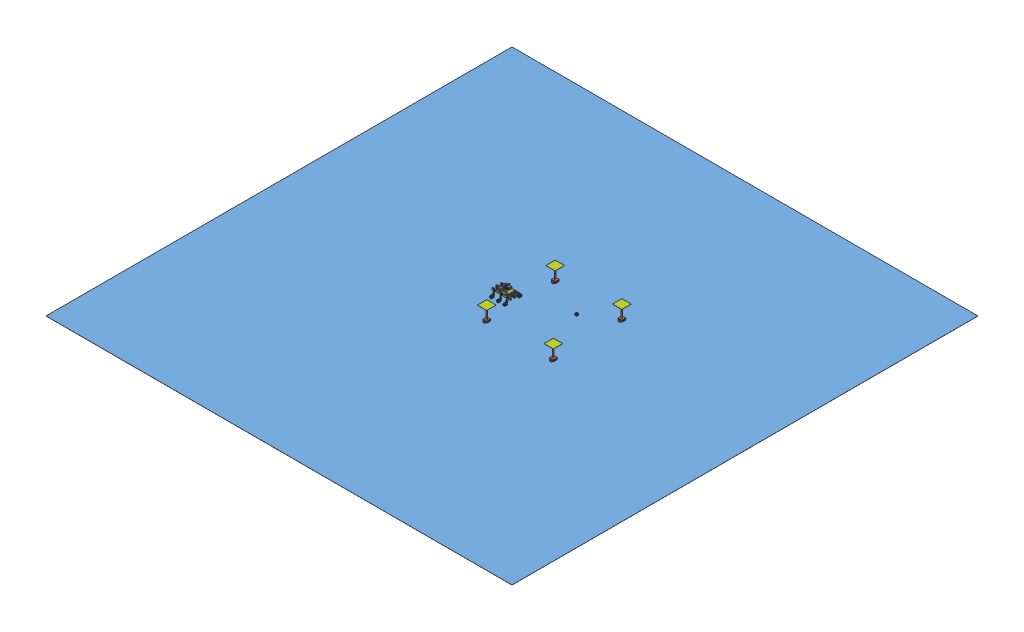
SolidWorks assembly Assamblu, configuration Default. Lengths in mm.
Overall size (50000 1818.74 50000).
74 component instances, 15 part files, 10 mates.
Components (placement in the parent):
- luna-1: luna [Default] at (-9277.6396 23632.6067 54794.8958) size (50000 10 50000)
- pole-1: pole [Default] at (14093.9687 23008.1365 29556.7388) size (1000 1818.74 1000)
  - pilon-1: pilon [Default] at (750.6878 634.4701 2074.8363) size (400 1200 400)
  - fix-1: fix [Default] at (704.1878 324.4701 2336.3363) size (236 430 123)
    - screw - Copy-1: screw - Copy [Default] at origin size (83 330 83)
    - Part3^fix-1: Part3^fix [Default] at origin size (236 100 123) (virtual)
    - screw2 - Copy - Copy-1: screw2 - Copy - Copy [Default] at (97.0846 0 0) size (83 330 83)
  - fix-2: fix [Default] at (797.1878 324.4701 1813.3363) x (-1 0 0) z (0 0 -1) size (236 430 123)
    - screw - Copy-1: screw - Copy [Default] at origin size (83 330 83)
    - Part3^fix-1: Part3^fix [Default] at origin size (236 100 123) (virtual)
    - screw2 - Copy - Copy-1: screw2 - Copy - Copy [Default] at (97.0846 0 0) size (83 330 83)
  - pilon2-1: pilon2 [Default] at (750.6878 909.2097 2074.8363) x (-0.999521 0 0.03096) z (-0.03096 0 -0.999521) size (110 1000 110)
  - cap-2: cap [Default] at (750.6878 1909.2097 2074.8363) size (1000 264 1000)
- pole-2: pole [Default] at (21250.0931 23008.1365 29556.7388) size (1000 1818.74 1000)
  - pilon-1: pilon [Default] at (750.6878 634.4701 2074.8363) size (400 1200 400)
  - fix-1: fix [Default] at (704.1878 324.4701 2336.3363) size (236 430 123)
    - screw - Copy-1: screw - Copy [Default] at origin size (83 330 83)
    - Part3^fix-1: Part3^fix [Default] at origin size (236 100 123) (virtual)
    - screw2 - Copy - Copy-1: screw2 - Copy - Copy [Default] at (97.0846 0 0) size (83 330 83)
  - fix-2: fix [Default] at (797.1878 324.4701 1813.3363) x (-1 0 0) z (0 0 -1) size (236 430 123)
    - screw - Copy-1: screw - Copy [Default] at origin size (83 330 83)
    - Part3^fix-1: Part3^fix [Default] at origin size (236 100 123) (virtual)
    - screw2 - Copy - Copy-1: screw2 - Copy - Copy [Default] at (97.0846 0 0) size (83 330 83)
  - pilon2-1: pilon2 [Default] at (750.6878 909.2097 2074.8363) x (-0.999521 0 0.03096) z (-0.03096 0 -0.999521) size (110 1000 110)
  - cap-2: cap [Default] at (750.6878 1909.2097 2074.8363) size (1000 264 1000)
- pole-7: pole [Default] at (21250.0931 23008.1365 22209.27) size (1000 1818.74 1000)
  - pilon-1: pilon [Default] at (750.6878 634.4701 2074.8363) size (400 1200 400)
  - fix-1: fix [Default] at (704.1878 324.4701 2336.3363) size (236 430 123)
    - screw - Copy-1: screw - Copy [Default] at origin size (83 330 83)
    - Part3^fix-1: Part3^fix [Default] at origin size (236 100 123) (virtual)
    - screw2 - Copy - Copy-1: screw2 - Copy - Copy [Default] at (97.0846 0 0) size (83 330 83)
  - fix-2: fix [Default] at (797.1878 324.4701 1813.3363) x (-1 0 0) z (0 0 -1) size (236 430 123)
    - screw - Copy-1: screw - Copy [Default] at origin size (83 330 83)
    - Part3^fix-1: Part3^fix [Default] at origin size (236 100 123) (virtual)
    - screw2 - Copy - Copy-1: screw2 - Copy - Copy [Default] at (97.0846 0 0) size (83 330 83)
  - pilon2-1: pilon2 [Default] at (750.6878 909.2097 2074.8363) x (-0.999521 0 0.03096) z (-0.03096 0 -0.999521) size (110 1000 110)
  - cap-2: cap [Default] at (750.6878 1909.2097 2074.8363) size (1000 264 1000)
- pole-8: pole [Default] at (14093.9687 23008.1365 22209.27) size (1000 1818.74 1000)
  - pilon-1: pilon [Default] at (750.6878 634.4701 2074.8363) size (400 1200 400)
  - fix-1: fix [Default] at (704.1878 324.4701 2336.3363) size (236 430 123)
    - screw - Copy-1: screw - Copy [Default] at origin size (83 330 83)
    - Part3^fix-1: Part3^fix [Default] at origin size (236 100 123) (virtual)
    - screw2 - Copy - Copy-1: screw2 - Copy - Copy [Default] at (97.0846 0 0) size (83 330 83)
  - fix-2: fix [Default] at (797.1878 324.4701 1813.3363) x (-1 0 0) z (0 0 -1) size (236 430 123)
    - screw - Copy-1: screw - Copy [Default] at origin size (83 330 83)
    - Part3^fix-1: Part3^fix [Default] at origin size (236 100 123) (virtual)
    - screw2 - Copy - Copy-1: screw2 - Copy - Copy [Default] at (97.0846 0 0) size (83 330 83)
  - pilon2-1: pilon2 [Default] at (750.6878 909.2097 2074.8363) x (-0.999521 0 0.03096) z (-0.03096 0 -0.999521) size (110 1000 110)
  - cap-2: cap [Default] at (750.6878 1909.2097 2074.8363) size (1000 264 1000)
- arm-1: arm [Default] at (20261.8878 24827.3463 27389.894) size (300 300 300)
- lg-1: lg [Default] at (13689.7324 24126.6075 28424.3393) size (2000 1056.21 1833.55)
  - act2-1: act2 [Default] at (710 -374.097 990.1927) x (0 1 0) z (1 0 0) size (227.86 360.36 100)
  - Wheel-1: Wheel [Default] at (710 -349.0008 1023.6376) x (0 1 0) z (0 0 -1) size (274.42 270 250)
  - act1-1: act1 [Default] at (710 -171.1455 626.4214) x (-1 0 0) z (0 0 -1) size (180 401.15 176.42)
  - body-1: body [Default] at origin size (2000 400 1000)
  - act1-2: act1 [Default] at (-710 -171.1455 626.4214) x (-1 0 0) z (0 0 -1) size (180 401.15 176.42)
  - Wheel-2: Wheel [Default] at (-710 -349.0008 1023.6376) x (-1 0 0) z (0 0 -1) size (274.42 270 250)
  - act2-2: act2 [Default] at (-710 -374.097 990.1927) x (0 1 0) z (1 0 0) size (227.86 360.36 100)
  - Wheel-3: Wheel [Default] at (-710 -349.0008 -1023.6376) size (274.42 270 250)
  - act2-3: act2 [Default] at (-710 -374.097 -990.1927) x (0 1 0) z (-1 0 0) size (227.86 360.36 100)
  - act1-3: act1 [Default] at (-710 -171.1455 -626.4214) size (180 401.15 176.42)
  - act1-4: act1 [Default] at (710 -171.1455 -626.4214) size (180 401.15 176.42)
  - Wheel-4: Wheel [Default] at (710 -349.0008 -1023.6376) x (0 -1 0) z (0 0 1) size (274.42 270 250)
  - act2-4: act2 [Default] at (710 -374.097 -990.1927) x (0 1 0) z (-1 0 0) size (227.86 360.36 100)
  - tool box-1: tool box [Default] at (-340 200 0) x (0 0 1) z (-1 0 0) size (980 200 300)
  - act1-5: act1 [Default] at (50 -171.1455 626.4214) x (-1 0 0) z (0 0 -1) size (180 401.15 176.42)
  - act2-5: act2 [Default] at (50 -374.097 990.1927) x (0 1 0) z (1 0 0) size (227.86 360.36 100)
  - Wheel-5: Wheel [Default] at (50 -349.0008 1023.6376) x (-1 0 0) z (0 0 -1) size (274.42 270 250)
  - arm-1: arm [Default] at (0 400 0) x (0.719935 0 0.694042) z (-0.694042 0 0.719935) size (300 300 300)
  - Lab-1: Lab [Default] at (10 200 -340) x (0 0 1) z (-1 0 0) size (324.09 330 324.09)
  - Wheel-6: Wheel [Default] at (50 -349.0008 -1023.6376) size (274.42 270 250)
  - act1-6: act1 [Default] at (50 -171.1455 -626.4214) size (180 401.15 176.42)
  - act2-6: act2 [Default] at (50 -374.097 -990.1927) x (0 1 0) z (-1 0 0) size (227.86 360.36 100)
  - solar panel-1: solar panel [Default] at (150 200 330) size (600 10 300)
Mates (geometry in assembly coordinates):
- Coincident1: coincident: plane of luna-1 through (-9277.6396 23642.6067 54794.8958) normal (0 1 0); plane of pole-1/pilon-1 through (14844.6565 23642.6067 31631.5751) normal (0 -1 0)
- Coincident2: coincident: plane of luna-1 through (-9277.6396 23642.6067 54794.8958) normal (0 1 0); plane of pole-2/pilon-1 through (22000.7809 23642.6067 31631.5751) normal (0 -1 0)
- Coincident3: coincident: plane of luna-1 through (-9277.6396 23642.6067 54794.8958) normal (0 1 0); plane of pole-7/pilon-1 through (22000.7809 23642.6067 24284.1063) normal (0 -1 0)
- Coincident4: coincident: plane of luna-1 through (-9277.6396 23642.6067 54794.8958) normal (0 1 0); plane of pole-8/pilon-1 through (14844.6565 23642.6067 24284.1063) normal (0 -1 0)
- Distance1: distance = 0 mm: plane of pole-7/pilon-1 through (22200.7809 23842.6067 24484.1063) normal (1 0 0); plane of pole-2/pilon-1 through (22200.7809 23842.6067 31831.5751) normal (1 0 0)
- Distance2: distance = 0 mm: plane of pole-2/pilon-1 through (22200.7809 23842.6067 31831.5751) normal (0 0 1); plane of pole-1/pilon-1 through (15044.6565 23842.6067 31831.5751) normal (0 0 1)
- Distance3: distance = 0 mm: plane of pole-8/pilon-1 through (14644.6565 23842.6067 24484.1063) normal (-1 0 0); plane of pole-1/pilon-1 through (14644.6565 23842.6067 31831.5751) normal (-1 0 0)
- Distance4: distance = 0 mm: plane of pole-8/pilon-1 through (15044.6565 23842.6067 24084.1063) normal (0 0 -1); plane of pole-7/pilon-1 through (22200.7809 23842.6067 24084.1063) normal (0 0 -1)
- Distance5: distance = 0 mm: plane of arm-1 through (20261.8878 24927.3463 27389.894) normal (0 1 0); plane of pole-8/cap-2 through (14844.6565 24927.3463 24284.1063) normal (0 1 0)
- Coincident5: coincident: plane of luna-1 through (-9277.6396 23642.6067 54794.8958) normal (0 1 0); plane of lg-1/Wheel-2 through (12979.7324 23642.6067 29341.116) normal (0 -1 0)
